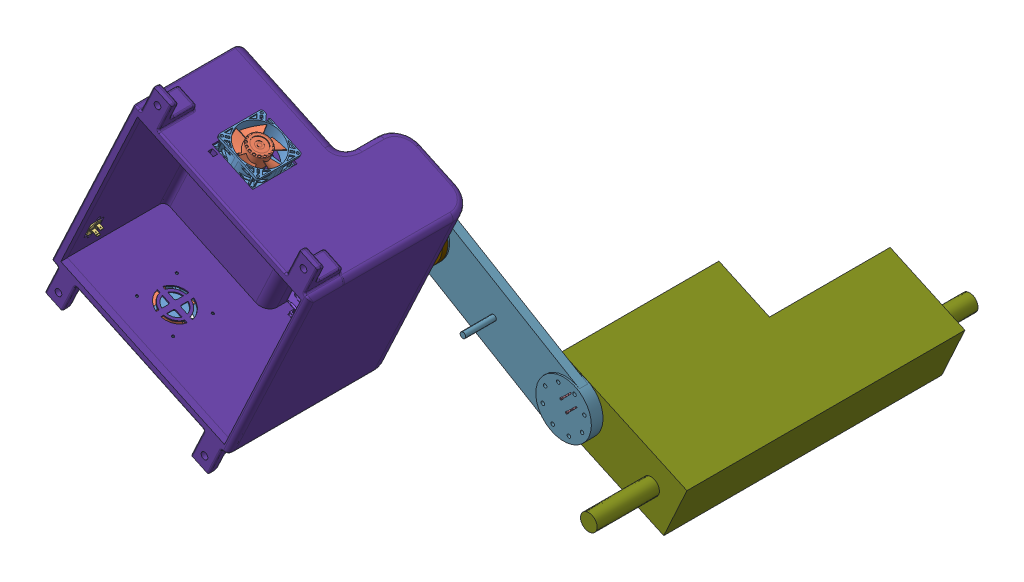
SolidWorks assembly final_design, configuration Default. Lengths in mm.
Overall size (805.78 606.9 971.54).
50 component instances, 26 part files, 44 mates.
Components (placement in the parent):
- BaseMotorCAD-2: BaseMotorCAD [Default] at (-115.7644 -2.9526 1479.9466) x (0 0 1) z (0.420434 0.907323 0) size (206.2 42 78.2)
  - BaseMotorCAD.stp-1: BaseMotorCAD.stp [默认] at origin size (206.2 42 78.2)
    - 0.stp-1: 0.stp [Default] at origin size (20 4 4)
    - 0-0.stp-1: 0-0.stp [默认] at origin size (30.5 12 12)
    - 0-1.stp-1: 0-1.stp [默认] at origin size (7 14.3 16)
    - 0-2.stp-1: 0-2.stp [默认] at origin size (8 28 28)
    - 0-3.stp-1: 0-3.stp [Default] at origin size (61.95 42 42)
    - 0-4.stp-1: 0-4.stp [Default] at origin size (12.4 42 42)
    - 0-5.stp-1: 0-5.stp [Default] at origin size (13.5 42 42)
    - 0-6.stp-1: 0-6.stp [Default] at origin size (20.95 30 72.2)
    - 0-7.stp-1: 0-7.stp [Default] at origin size (2.3 29.7 30)
    - 0-8.stp-1: 0-8.stp [Default] at origin size (3.5 34.51 34.68)
    - 0-9.stp-1: 0-9.stp [Default] at origin size (6.99 3.52 30.53)
    - 0-10.stp-1: 0-10.stp [默认] at origin size (2.9 34.8 33.85)
    - 0-11.stp-1: 0-11.stp [默认] at origin size (64.7 35 35)
- long_arm-3: long_arm [默认] at (116.6911 -199.0761 1422.4466) x (0.859922 -0.510425 0) z (0 0 1) size (400 100 106)
- 60355K43_Ball Bearing-1: 60355K43_Ball Bearing [60355K43] at (142.2123 -156.08 1416.9574) x (-1 0.000445 0) z (0 0 1) size (15.88 15.88 4.98) (hidden)
- 60355K43_Ball Bearing-2: 60355K43_Ball Bearing [60355K43] at (142.2123 -156.08 1411.979) x (0.999999 0.001571 0) z (0 0 1) size (15.88 15.88 4.98) (hidden)
- 90332A137_High-Profile Socket Head Screw-1: 90332A137_High-Profile Socket Head Screw [90332A137] at (-135.4312 -36.0857 1459.5466) x (-0.229698 0.973262 0) z (0 0 1) size (9.53 9.53 48.43)
- 90332A137_High-Profile Socket Head Screw-2: 90332A137_High-Profile Socket Head Screw [90332A137] at (-106.2423 -40.2878 1459.5466) x (0.901564 0.432645 0) z (0 0 1) size (9.53 9.53 48.43)
- short_arm-1: short_arm [默认] at (181.5173 -125.175 1406.4898) x (-0.6181 0.7861 0) z (0 0 1) size (250 100 63) (hidden)
- 91290A346_Black-Oxide Alloy Steel Socket Head Screw-1: 91290A346_Black-Oxide Alloy Steel Socket Head Screw [91290A346] at (142.2123 -156.08 1410.9466) size (10 10 71.46) (hidden)
- 90332A137_High-Profile Socket Head Screw-4: 90332A137_High-Profile Socket Head Screw [90332A137] at (103.9548 -151.5028 1417.1918) size (9.53 9.53 48.43) (hidden)
- 90332A137_High-Profile Socket Head Screw-5: 90332A137_High-Profile Socket Head Screw [90332A137] at (118.3967 -125.7913 1417.1918) x (0.628634 0.777701 0) z (0 0 1) size (9.53 9.53 48.43) (hidden)
- top-1: top [默认] at (132.8328 -176.5318 1386.4466) x (0.416867 0.908968 0) z (-0.908968 0.416867 0) size (101.91 723.04 248)
- NewBase-1: NewBase [Default] at (-206.3275 39.4541 1779.9466) x (0.424067 0.905631 0) z (0 0 -1) size (460 350 300)
- connector_long-2: connector_long [默认] at (-115.7644 -2.9526 1450.4466) x (-0.859922 0.510425 0) z (-0.510425 -0.859922 0) size (100 35.5 100)
- 8312_NL_ebm-papst-1: 8312_NL_ebm-papst [8312 NL_ebm-papst] at (-307.9956 -95.1327 1689.9466) x (-0.905631 0.424067 0) z (-0.424067 -0.905631 0) size (80 80 32.13)
  - Fan-House_8312_NL_ebm-papst-1: Fan-House_8312_NL_ebm-papst [8312 NL_ebm-papst] at origin size (80 80 32)
  - Fan_8312_NL_ebm-papst-1: Fan_8312_NL_ebm-papst [8312 NL_ebm-papst] x (0 0 -1) z (0.028627 -0.99959 0) size (27.13 74 74)
- 8312_NL_ebm-papst-2: 8312_NL_ebm-papst [8312 NL_ebm-papst] at (-168.0536 203.7255 1689.9466) x (0.905631 -0.424067 0) z (0.424067 0.905631 0) size (80 80 32.13)
  - Fan-House_8312_NL_ebm-papst-1: Fan-House_8312_NL_ebm-papst [8312 NL_ebm-papst] at origin size (80 80 32)
  - Fan_8312_NL_ebm-papst-1: Fan_8312_NL_ebm-papst [8312 NL_ebm-papst] x (0 0 -1) z (0.028627 -0.99959 0) size (27.13 74 74)
- connector_short-1: connector_short [默认] at (142.2123 -156.08 1378.4898) x (0.7861 0.6181 0) z (0.6181 -0.7861 0) size (100 43 100) (hidden)
- ACPowerPort-2: ACPowerPort [默认] at (-413.812 9.024 1740.9466) x (-0.424067 -0.905631 0) z (-0.905631 0.424067 0) size (52 22 28.65)
- ArmMotorCAD-1: ArmMotorCAD [Default] at (142.2123 -156.08 1376.4466) x (0 0 -1) z (0.859922 -0.510425 0) size (206.2 42 78.2)
  - ArmMotorCAD.stp-1: ArmMotorCAD.stp [Default] at origin size (206.2 42 78.2)
    - 0.stp-1: 0.stp [Default] at origin size (20 4 4)
    - 0-0.stp-1: 0-0.stp [默认] at origin size (30.5 12 12)
    - 0-1.stp-1: 0-1.stp [默认] at origin size (7 14.3 16)
    - 0-2.stp-1: 0-2.stp [默认] at origin size (8 28 28)
    - 0-3.stp-1: 0-3.stp [Default] at origin size (61.95 42 42)
    - 0-4.stp-1: 0-4.stp [Default] at origin size (12.4 42 42)
    - 0-5.stp-1: 0-5.stp [Default] at origin size (13.5 42 42)
    - 0-6.stp-1: 0-6.stp [Default] at origin size (20.95 30 72.2)
    - 0-7.stp-1: 0-7.stp [Default] at origin size (2.3 29.7 30)
    - 0-8.stp-1: 0-8.stp [Default] at origin size (3.5 34.51 34.68)
    - 0-9.stp-1: 0-9.stp [Default] at origin size (6.99 3.52 30.53)
- 91251A102_Black-Oxide Alloy Steel Socket Head Screw-4: 91251A102_Black-Oxide Alloy Steel Socket Head Screw [91251A102] at (184.7655 -121.8248 1468.9808) size (3.57 3.57 18.42)
- 91251A102_Black-Oxide Alloy Steel Socket Head Screw-5: 91251A102_Black-Oxide Alloy Steel Socket Head Screw [91251A102] at (168.9894 -110.8729 1463.317) size (3.57 3.57 18.42)
Mates (geometry in assembly coordinates):
- 重合42: coincident anti-aligned: plane of long_arm-3 through (142.2123 -156.08 1419.4466) normal (0 0 -1); plane of 60355K43_Ball Bearing-1 through (142.2089 -163.7686 1419.4466) normal (0 0 1)
- 重合62: coincident anti-aligned: plane of 60355K43_Ball Bearing-1 through (142.2089 -163.7686 1414.4682) normal (0 0 -1); plane of 60355K43_Ball Bearing-2 through (142.2003 -148.3914 1414.4682) normal (0 0 1)
- 重合68: coincident anti-aligned: plane of long_arm-3 through (142.2123 -156.08 1419.4466) normal (0 0 -1); plane of 60355K43_Ball Bearing-1 through (142.2089 -163.7686 1419.4466) normal (0 0 1)
- 重合83: coincident anti-aligned: plane of 60355K43_Ball Bearing-2 through (142.2003 -148.3914 1409.4898) normal (0 0 -1); plane of short_arm-1 through (181.5173 -125.175 1409.4898) normal (0 0 1)
- 同心59: concentric aligned: circle of 60355K43_Ball Bearing-1; circle of 60355K43_Ball Bearing-2
- 重合87: coincident anti-aligned: plane of 60355K43_Ball Bearing-2 through (142.2003 -148.3914 1409.4898) normal (0 0 -1); plane of short_arm-1 through (181.5173 -125.175 1409.4898) normal (0 0 1)
- 同心60: concentric aligned: circle of 60355K43_Ball Bearing-2; circle of short_arm-1
- 重合90: coincident anti-aligned: plane of long_arm-3 through (142.2123 -156.08 1440.4466) normal (0 0 1); plane of 91290A346_Black-Oxide Alloy Steel Socket Head Screw-1 through (142.2123 -151.38 1440.4466) normal (0 0 -1)
- 同心61: concentric anti-aligned: circle of long_arm-3; circle of 91290A346_Black-Oxide Alloy Steel Socket Head Screw-1
- 同心63: concentric aligned: circle of short_arm-1; circle of 90332A137_High-Profile Socket Head Screw-4
- 同心65: concentric anti-aligned: circle of 60355K43_Ball Bearing-1; circle of 91290A346_Black-Oxide Alloy Steel Socket Head Screw-1
- 同心69: concentric aligned: circle of short_arm-1; circle of 90332A137_High-Profile Socket Head Screw-5
- 重合108: coincident aligned: plane of BaseMotorCAD-2/BaseMotorCAD.stp-1/0-5.stp-1 through (-115.7644 -2.9526 1479.9466) normal (0 0 -1); plane of NewBase-1 through (-206.3275 39.4541 1479.9466) normal (0 0 -1)
- 同心80: concentric anti-aligned: cone of BaseMotorCAD-2/BaseMotorCAD.stp-1/0-5.stp-1 through (-121.7894 13.4776 1480.1216) axis (0 0 1); circle of NewBase-1
- 重合110: coincident anti-aligned: circle of BaseMotorCAD-2/BaseMotorCAD.stp-1/0-5.stp-1; circle of NewBase-1
- 重合111: coincident anti-aligned: plane of BaseMotorCAD-2/BaseMotorCAD.stp-1/0-1.stp-1 through (-113.0973 -4.4202 1475.9466) normal (0 0 -1); plane of connector_long-2 through (-115.7644 -2.9526 1475.9466) normal (0 0 1)
- 同心81: concentric anti-aligned: circle of BaseMotorCAD-2/BaseMotorCAD.stp-1/0-2.stp-1; circle of connector_long-2
- 重合112: coincident anti-aligned: plane of long_arm-3 through (-115.7644 -2.9526 1440.4466) normal (0 0 1); plane of connector_long-2 through (-115.7644 -2.9526 1440.4466) normal (0 0 -1)
- 重合113: coincident anti-aligned: plane of long_arm-3 through (-115.7644 -2.9526 1421.4466) normal (0 0 -1); plane of 90332A137_High-Profile Socket Head Screw-2 through (-106.2423 -40.2878 1421.4466) normal (0 0 1)
- 同心82: concentric anti-aligned: circle of 90332A137_High-Profile Socket Head Screw-2; circle of connector_long-2
- 同心83: concentric anti-aligned: circle of 90332A137_High-Profile Socket Head Screw-2; circle of connector_long-2
- 重合114: coincident anti-aligned: plane of long_arm-3 through (-115.7644 -2.9526 1421.4466) normal (0 0 -1); plane of 90332A137_High-Profile Socket Head Screw-1 through (-135.4312 -36.0857 1421.4466) normal (0 0 1)
- 同心84: concentric anti-aligned: circle of 90332A137_High-Profile Socket Head Screw-1; circle of connector_long-2
- 同心85: concentric anti-aligned: circle of 90332A137_High-Profile Socket Head Screw-1; circle of connector_long-2
- 同心86: concentric anti-aligned: circle of long_arm-3; circle of 90332A137_High-Profile Socket Head Screw-1
- 同心87: concentric aligned: circle of 90332A137_High-Profile Socket Head Screw-2; circle of connector_long-2
- 同心88: concentric anti-aligned: circle of long_arm-3; circle of 90332A137_High-Profile Socket Head Screw-2
- 重合116: coincident anti-aligned: plane of NewBase-1 through (-276.2985 -109.9751 1779.9466) normal (-0.424067 -0.905631 0); plane of 8312_NL_ebm-papst-1/Fan-House_8312_NL_ebm-papst-1 through (-340.3719 -79.9723 1725.6966) normal (0.424067 0.905631 0)
- 同心90: concentric anti-aligned: circle of NewBase-1; circle of 8312_NL_ebm-papst-1/Fan-House_8312_NL_ebm-papst-1
- 同心91: concentric anti-aligned: circle of NewBase-1; circle of 8312_NL_ebm-papst-1/Fan-House_8312_NL_ebm-papst-1
- 重合117: coincident anti-aligned: plane of NewBase-1 through (-136.3565 188.8832 1779.9466) normal (0.424067 0.905631 0); plane of 8312_NL_ebm-papst-2/Fan-House_8312_NL_ebm-papst-1 through (-135.6773 188.5651 1725.6966) normal (-0.424067 -0.905631 0)
- 同心92: concentric aligned: circle of NewBase-1; circle of 8312_NL_ebm-papst-2/Fan-House_8312_NL_ebm-papst-1
- 同心93: concentric anti-aligned: circle of NewBase-1; circle of 8312_NL_ebm-papst-2/Fan-House_8312_NL_ebm-papst-1
- 同心94: concentric anti-aligned: circle of 91290A346_Black-Oxide Alloy Steel Socket Head Screw-1; circle of connector_short-1
- 重合119: coincident anti-aligned: plane of short_arm-1 through (181.5173 -125.175 1388.4898) normal (0 0 -1); plane of connector_short-1 through (142.2123 -156.08 1388.4898) normal (0 0 1)
- 同心95: concentric anti-aligned: circle of 90332A137_High-Profile Socket Head Screw-5; circle of connector_short-1
- 同心96: concentric anti-aligned: circle of 90332A137_High-Profile Socket Head Screw-4; circle of connector_short-1
- 重合125: coincident anti-aligned: plane of NewBase-1 through (-364.8129 113.6657 1579.9466) normal (-0.905631 0.424067 0); plane of ACPowerPort-2 through (-418.0527 -0.0324 1734.9466) normal (0.905631 -0.424067 0)
- 重合126: coincident aligned: line of NewBase-1 through (-419.9416 -4.0663 1751.9466) axis (0.424067 0.905631 0); line of ACPowerPort-2 through (-418.0527 -0.0324 1751.9466) axis (0.424067 0.905631 0)
- 同心97: concentric aligned: circle of long_arm-3; circle of top-1
- 重合129: coincident anti-aligned: plane of long_arm-3 through (142.2123 -156.08 1419.4466) normal (0 0 -1); plane of top-1 through (178.2812 -197.3751 1419.4466) normal (0 0 1)
- 重合130: coincident anti-aligned: plane of top-1 through (132.8328 -176.5318 1376.4466) normal (0 0 -1); plane of ArmMotorCAD-1/ArmMotorCAD.stp-1/0-5.stp-1 through (142.2123 -156.08 1376.4466) normal (0 0 1)
- 同心98: concentric anti-aligned: circle of top-1; circle of ArmMotorCAD-1/ArmMotorCAD.stp-1/0-2.stp-1
- 平行1: parallel anti-aligned: plane of long_arm-3 through (123.7855 -203.2871 1386.4466) normal (-0.859922 0.510425 0); plane of ArmMotorCAD-1/ArmMotorCAD.stp-1/0.stp-1 through (148.6617 -159.9082 1393.9466) normal (0.859922 -0.510425 0)
